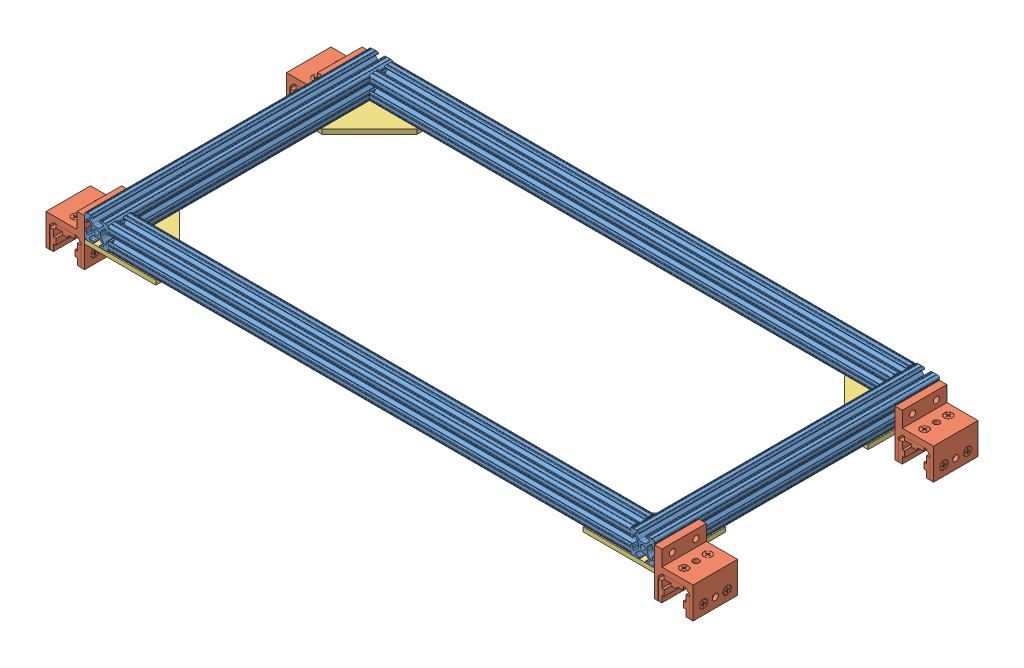
SolidWorks assembly slide-carriage, configuration Default. Lengths in mm.
Overall size (692.1 53.97 304.8).
12 component instances, 3 part files, 33 mates.
Components (placement in the parent):
- 8020-1010 X 12-2: 8020-1010 X 12 [12in] at origin size (25.4 25.4 304.8)
- 8020-1010 X 12-3: 8020-1010 X 12 [12in] at (-584.2 0 0) size (25.4 25.4 304.8)
- 8020-1010 X 12-4: 8020-1010 X 12 [22in] at (-12.7 0 -292.1) x (0 0 -1) z (1 0 0) size (25.4 25.4 558.8)
- 8020-1010 X 12-5: 8020-1010 X 12 [22in] at (-12.7 0 -12.7) x (0 0 1) z (1 0 0) size (25.4 25.4 558.8)
- 60585K180-1: 60585K180 [60585K18] at (33.3248 -41.275 -280.9875) size (41.25 49.99 47.62)
- 60585K180-2: 60585K180 [60585K18] at (33.3248 -41.275 -23.8125) size (41.25 49.99 47.62)
- 60585K180-3: 60585K180 [60585K18] at (-617.5248 -41.275 -280.9875) x (-1 0 0) z (0 0 -1) size (41.25 49.99 47.62)
- 60585K180-4: 60585K180 [60585K18] at (-617.5248 -41.275 -23.8125) x (-1 0 0) z (0 0 -1) size (41.25 49.99 47.62)
- 47065T177_3in-90plate-1: 47065T177_3in-90plate [47065T177] at (-38.1 -17.4625 -50.8) x (0 0 1) z (0 -1 0) size (76.2 76.2 4.76)
- 47065T177_3in-90plate-2: 47065T177_3in-90plate [47065T177] at (-546.1 -17.4625 -50.8) x (-1 0 0) z (0 -1 0) size (76.2 76.2 4.76)
- 47065T177_3in-90plate-3: 47065T177_3in-90plate [47065T177] at (-546.1 -12.7 -254) x (-1 0 0) z (0 1 0) size (76.2 76.2 4.76)
- 47065T177_3in-90plate-4: 47065T177_3in-90plate [47065T177] at (-38.1 -12.7 -254) x (0 0 -1) z (0 1 0) size (76.2 76.2 4.76)
Mates (geometry in assembly coordinates):
- Coincident2: coincident aligned: plane of 8020-1010 X 12-2 through (-9.5504 12.7 -304.8) normal (0 1 0); plane of 8020-1010 X 12-3 through (-574.6496 12.7 -304.8) normal (0 1 0)
- Coincident3: coincident aligned: plane of 8020-1010 X 12-2 through (-1.7093 -7.6708 -304.8) normal (0 0 -1); circle of 8020-1010 X 12-3
- Coincident4: coincident aligned: plane of 8020-1010 X 12-2 through (-1.7093 -7.6708 -304.8) normal (0 0 -1); plane of 8020-1010 X 12-4 through (-571.5 6.3331 -304.8) normal (0 0 -1)
- Coincident5: coincident anti-aligned: plane of 8020-1010 X 12-2 through (-12.7 6.3331 -304.8) normal (-1 0 0); plane of 8020-1010 X 12-4 through (-12.7 -7.6708 -290.3907) normal (1 0 0)
- Coincident6: coincident aligned: plane of 8020-1010 X 12-2 through (6.3331 -12.7 -304.8) normal (0 -1 0); plane of 8020-1010 X 12-4 through (-571.5 -12.7 -285.7669) normal (0 -1 0)
- Coincident9: coincident aligned: plane of 8020-1010 X 12-2 through (-1.7093 -7.6708 0) normal (0 0 1); plane of 8020-1010 X 12-5 through (-571.5 9.5504 0) normal (0 0 1)
- Coincident10: coincident anti-aligned: plane of 8020-1010 X 12-2 through (-12.7 -9.5504 -304.8) normal (-1 0 0); plane of 8020-1010 X 12-5 through (-12.7 7.6708 -14.4093) normal (1 0 0)
- Coincident11: coincident aligned: plane of 8020-1010 X 12-2 through (-9.5504 12.7 -304.8) normal (0 1 0); plane of 8020-1010 X 12-5 through (-571.5 12.7 -6.3669) normal (0 1 0)
- Distance3: distance = 558.8 mm anti-aligned: plane of 8020-1010 X 12-3 through (-571.5 6.3331 -304.8) normal (1 0 0); plane of 8020-1010 X 12-2 through (-12.7 6.3331 -304.8) normal (-1 0 0)
- Coincident12: coincident anti-aligned: plane of 8020-1010 X 12-2 through (12.7 -9.5504 -304.8) normal (1 0 0); plane of 60585K180-1 through (12.7 -7.9502 -257.175) normal (-1 0 0)
- Coincident13: coincident aligned: plane of 8020-1010 X 12-2 through (-1.7093 -7.6708 -304.8) normal (0 0 -1); plane of 60585K180-1 through (12.7 -41.275 -304.8) normal (0 0 -1)
- Distance4: distance = 3.9878 mm aligned: plane of 60585K180-1 through (12.7 8.7122 -232.8363) normal (0 1 0); plane of 8020-1010 X 12-2 through (9.5504 12.7 -304.8) normal (0 1 0)
- Coincident15: coincident aligned: plane of 8020-1010 X 12-2 through (-1.7093 -7.6708 0) normal (0 0 1); plane of 60585K180-2 through (12.7 -41.275 0) normal (0 0 1)
- Coincident16: coincident anti-aligned: plane of 8020-1010 X 12-2 through (12.7 6.3331 -304.8) normal (1 0 0); plane of 60585K180-2 through (12.7 -7.9502 0) normal (-1 0 0)
- Coincident17: coincident aligned: plane of 60585K180-1 through (12.7 -7.9502 -257.175) normal (0 1 0); plane of 60585K180-2 through (12.7 -7.9502 0) normal (0 1 0)
- Coincident18: coincident anti-aligned: plane of 8020-1010 X 12-3 through (-596.9 6.3331 -304.8) normal (-1 0 0); plane of 60585K180-3 through (-596.9 -7.9502 -304.8) normal (1 0 0)
- Coincident19: coincident aligned: plane of 8020-1010 X 12-3 through (-585.9093 -7.6708 -304.8) normal (0 0 -1); plane of 60585K180-3 through (-596.9 -41.275 -304.8) normal (0 0 -1)
- Coincident20: coincident aligned: plane of 60585K180-1 through (12.7 -7.9502 -257.175) normal (0 1 0); plane of 60585K180-3 through (-596.9 -7.9502 -304.8) normal (0 1 0)
- Coincident21: coincident anti-aligned: plane of 8020-1010 X 12-3 through (-596.9 6.3331 -304.8) normal (-1 0 0); plane of 60585K180-4 through (-596.9 -7.9502 -47.625) normal (1 0 0)
- Coincident22: coincident aligned: plane of 8020-1010 X 12-3 through (-585.9093 -7.6708 0) normal (0 0 1); plane of 60585K180-4 through (-596.9 -41.275 0) normal (0 0 1)
- Coincident23: coincident aligned: plane of 60585K180-3 through (-596.9 -7.9502 -304.8) normal (0 1 0); plane of 60585K180-4 through (-596.9 -7.9502 -47.625) normal (0 1 0)
- Coincident24: coincident anti-aligned: plane of 8020-1010 X 12-5 through (-571.5 -12.7 -3.1496) normal (0 -1 0); plane of 47065T177_3in-90plate-1 through (-63.5 -12.7 -25.4) normal (0 1 0)
- Coincident25: coincident aligned: plane of 8020-1010 X 12-5 through (-571.5 -6.3331 0) normal (0 0 1); plane of 47065T177_3in-90plate-1 through (-63.5 -12.7 0) normal (0 0 1)
- Coincident26: coincident aligned: plane of 8020-1010 X 12-2 through (12.7 -9.5504 -304.8) normal (1 0 0); plane of 47065T177_3in-90plate-1 through (12.7 -12.7 0) normal (1 0 0)
- Coincident27: coincident anti-aligned: plane of 8020-1010 X 12-5 through (-571.5 -12.7 -3.1496) normal (0 -1 0); plane of 47065T177_3in-90plate-2 through (-571.5 -12.7 -76.2) normal (0 1 0)
- Coincident28: coincident aligned: plane of 8020-1010 X 12-3 through (-596.9 -9.5504 -304.8) normal (-1 0 0); plane of 47065T177_3in-90plate-2 through (-596.9 -12.7 -76.2) normal (-1 0 0)
- Coincident29: coincident aligned: plane of 8020-1010 X 12-5 through (-571.5 -6.3331 0) normal (0 0 1); plane of 47065T177_3in-90plate-2 through (-596.9 -12.7 0) normal (0 0 1)
- Coincident30: coincident anti-aligned: plane of 8020-1010 X 12-4 through (-571.5 -12.7 -298.4331) normal (0 -1 0); plane of 47065T177_3in-90plate-3 through (-571.5 -12.7 -228.6) normal (0 1 0)
- Coincident31: coincident aligned: plane of 8020-1010 X 12-3 through (-596.9 -9.5504 -304.8) normal (-1 0 0); plane of 47065T177_3in-90plate-3 through (-596.9 -17.4625 -228.6) normal (-1 0 0)
- Coincident32: coincident aligned: plane of 8020-1010 X 12-4 through (-571.5 -9.5504 -304.8) normal (0 0 -1); plane of 47065T177_3in-90plate-3 through (-596.9 -17.4625 -304.8) normal (0 0 -1)
- Coincident33: coincident anti-aligned: plane of 8020-1010 X 12-4 through (-571.5 -12.7 -285.7669) normal (0 -1 0); plane of 47065T177_3in-90plate-4 through (-63.5 -12.7 -279.4) normal (0 1 0)
- Coincident34: coincident aligned: plane of 8020-1010 X 12-2 through (12.7 -9.5504 -304.8) normal (1 0 0); plane of 47065T177_3in-90plate-4 through (12.7 -17.4625 -304.8) normal (1 0 0)
- Coincident35: coincident aligned: plane of 8020-1010 X 12-4 through (-571.5 -9.5504 -304.8) normal (0 0 -1); plane of 47065T177_3in-90plate-4 through (-63.5 -17.4625 -304.8) normal (0 0 -1)
